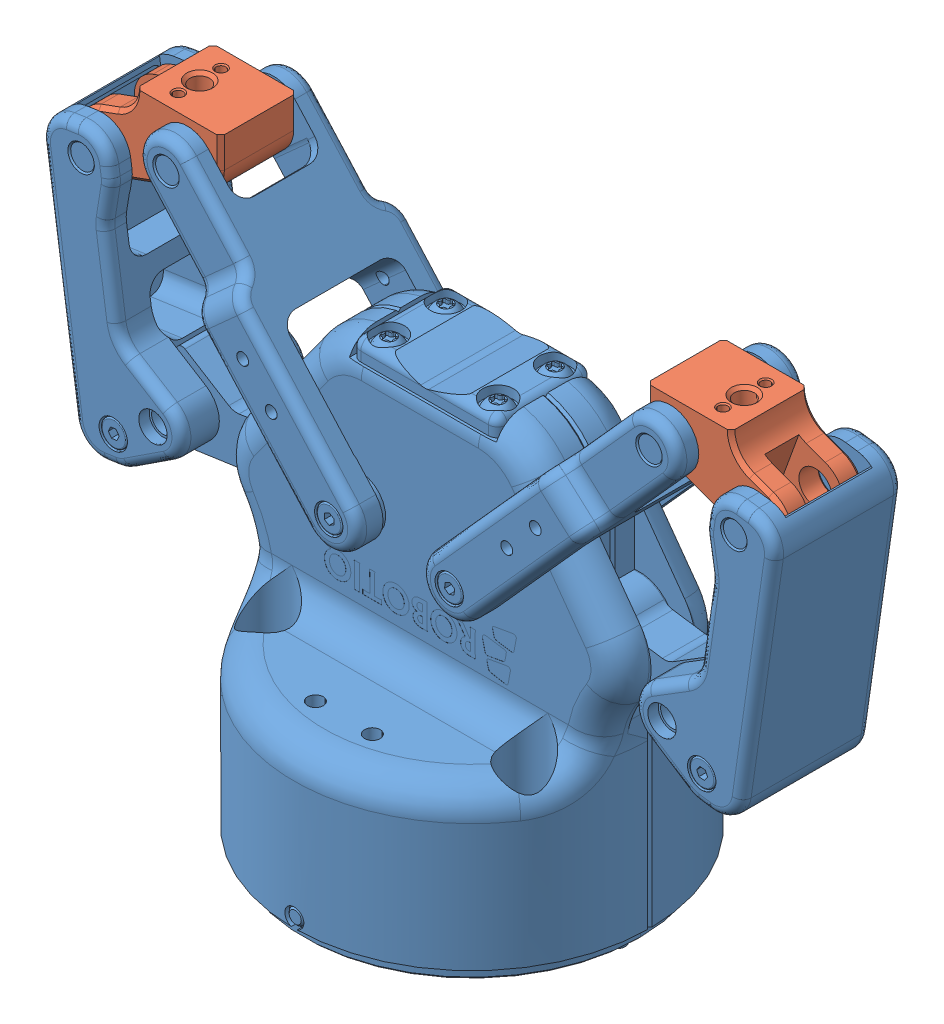
SolidWorks assembly 2F85-OPENED-NO_FINGER, configuration Default. Lengths in mm.
Overall size (154.57 113.82 75.02).
4 component instances, 2 part files, 0 mates.
Components (placement in the parent):
- 2F85-OPENED-NO_20FINGER_20181108.STEP-1: 2F85-OPENED-NO_20FINGER_20181108.STEP [Default] at origin size (154.57 113.82 75.02)
  - C-A01-85-OPENED.STEP-1: C-A01-85-OPENED.STEP [Default] at origin size (154.57 113.32 75.02)
  - C-049-DISTALE_DISTALE.STEP-1: C-049-DISTALE_DISTALE.STEP [Default] at (-50.9079 103.9203 0) x (0.000045 1 0) z (0 0 -1) size (19.02 29.9 16.2)
  - C-049-DISTALE_DISTALE.STEP-2: C-049-DISTALE_DISTALE.STEP [Default] at (50.9079 103.9203 0) x (-0.000045 1 0) z (0 0 1) size (19.02 29.9 16.2)
